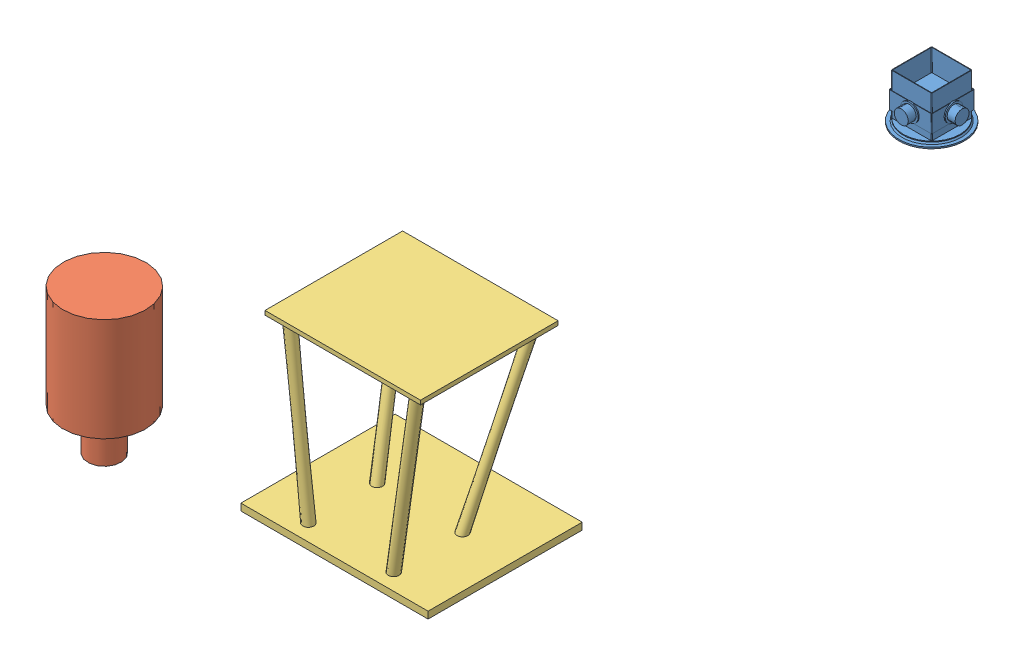
SolidWorks assembly Сборка1, configuration Default. Lengths in mm.
Overall size (1538.3 934.23 2079.53).
3 component instances, 3 part files, 2 mates.
Components (placement in the parent):
- detector9l_06102015-1: detector9l_06102015 [По умолчанию] at (109.9722 91.8324 128.3144) size (238 164.23 238)
- Neutron_generator-1: Neutron_generator [Default] at (-1122.2188 -153.1676 1901.7322) x (0.290534 0 -0.956865) z (0 -1 0) size (300 300 525)
- Столик_3-1: Столик_3 [Default] at (-226.351 91.8324 1681.5601) x (1 0 0) z (0 1 0) size (680 560 645)
Mates (geometry in assembly coordinates):
- Совпадение1: coincident anti-aligned: plane of detector9l_06102015-1 through (109.9722 91.8324 128.3144) normal (0 -1 0); plane of Столик_3-1 through (-226.351 91.8324 1681.5601) normal (0 1 0)
- Совпадение2: coincident anti-aligned: circle of Neutron_generator-1; plane of Столик_3-1 through (-226.351 -528.1676 1681.5601) normal (0 1 0)
